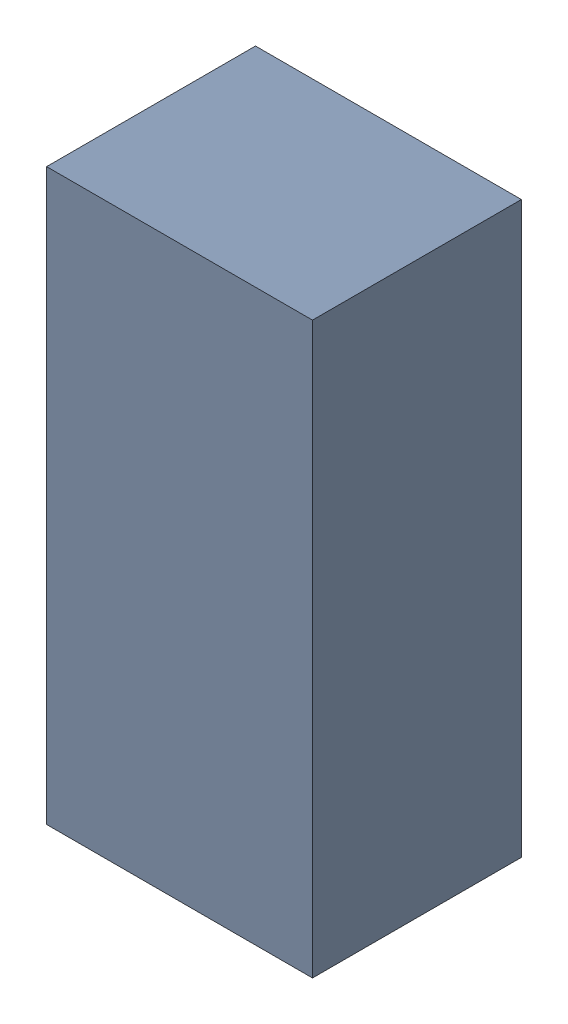
SolidWorks assembly D36, configuration Default. Lengths in mm.
Overall size (1.4 3 1.1).
2 component instances, 1 part files, 0 mates.
Components (placement in the parent):
- 5613955808-1: 5613955808 [Default] at (158 113.75 0) size (1.4 3 1.1)
  - Extruded_11-1: Extruded_11 [Default] at origin size (1.4 3 1.1)
